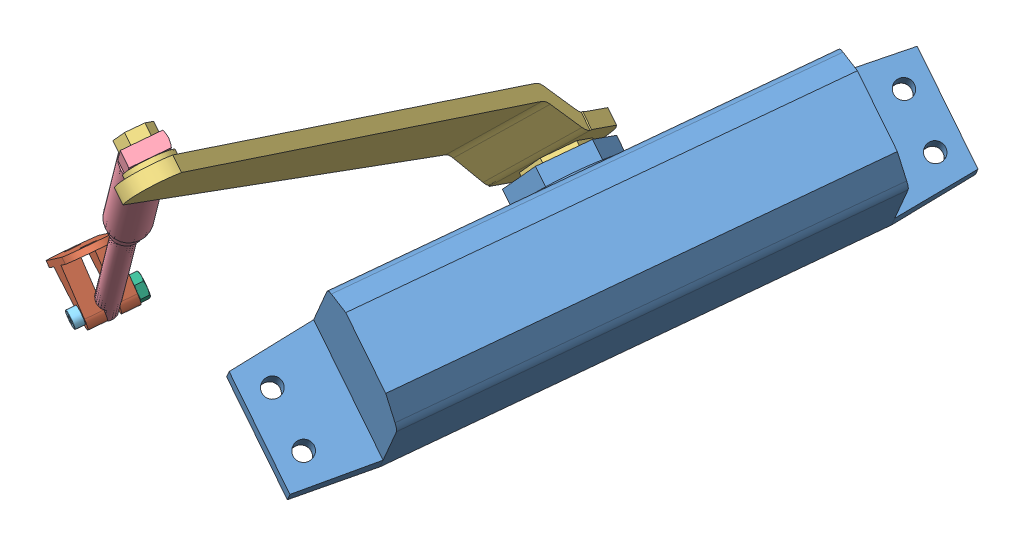
SolidWorks assembly Assem1, configuration Default. Lengths in mm.
Overall size (205.93 223.72 322.48).
6 component instances, 6 part files, 10 mates.
Components (placement in the parent):
- part 1-1: part 1 [Default] at (161.4245 634.4049 186.1692) x (0.375478 0.260914 -0.889348) z (0.74291 -0.65846 0.120476) size (195 65 63)
- part 2-1: part 2 [Default] at (50.7639 627.0627 264.9293) x (0.636002 0.592346 0.494599) z (0.401104 0.293798 -0.867639) size (55 20 15)
- part 3-1: part 3 [Default] at (133.3043 655.8535 186.2838) x (0.286267 0.47521 0.832002) z (-0.74291 0.65846 -0.120476) size (276 32 28)
- part 4-1: part 4 [Default] at (212.4075 806.2891 400.3454) x (-0.53591 -0.692902 -0.482377) z (-0.74291 0.65846 -0.120476) size (268 13 13)
- socket 1-1: socket 1 [Default] at (74.019 627.8079 274.8383) x (0.401104 0.293798 -0.867639) z (0.443113 -0.89121 -0.096932) size (20.28 5.5 5.5)
- socket 5-1: socket 5 [Default] at (83.2 626.6933 260.5341) x (-0.401104 -0.293798 0.867639) z (-0.443113 0.89121 0.096932) size (3 7.02 8.09)
Mates (geometry in assembly coordinates):
- Concentric4: concentric anti-aligned: circle of part 2-1; cylinder of socket 1-1 through (67.9968 622.8482 288.2538) axis (-0.401104 -0.293798 0.867639) radius 1.5
- Coincident5: coincident aligned: cylinder of socket 1-1 through (67.9968 622.8482 288.2538) axis (-0.401104 -0.293798 0.867639) radius 1.5; circle of socket 5-1
- Coincident6: coincident anti-aligned: plane of part 2-1 through (55.0907 627.7658 258.5235) normal (0.401104 0.293798 -0.867639); circle of socket 5-1
- Concentric11: concentric anti-aligned: cylinder of part 1-1 through (145.6626 675.3101 191.5153) axis (0.74291 -0.65846 0.120476) radius 4.5; cylinder of part 3-1 through (153.8347 668.0671 192.8405) axis (-0.74291 0.65846 -0.120476) radius 4.5
- Coincident11: coincident aligned: plane of part 1-1 through (140.623 652.8418 182.7959) normal (-0.74291 0.65846 -0.120476); circle of part 3-1
- Coincident14: coincident aligned: plane of part 2-1 through (49.0741 623.3588 271.5381) normal (-0.401104 -0.293798 0.867639); circle of socket 1-1
- Concentric24: concentric anti-aligned: cylinder of part 3-1 through (206.2629 802.3921 396.1852) axis (0.74291 -0.65846 0.120476) radius 3; cylinder of part 4-1 through (213.692 795.8075 397.3899) axis (-0.74291 0.65846 -0.120476) radius 2.5
- Coincident15: coincident aligned: plane of part 3-1 through (209.9775 799.0998 396.7876) normal (-0.74291 0.65846 -0.120476); circle of part 4-1
- Concentric25: concentric aligned: circle of part 4-1; cylinder of socket 1-1 through (67.9968 622.8482 288.2538) axis (-0.401104 -0.293798 0.867639) radius 1.5
- Coincident16: coincident aligned: plane of part 2-1 through (51.5661 627.6503 263.194) normal (-0.401104 -0.293798 0.867639); circle of part 4-1
